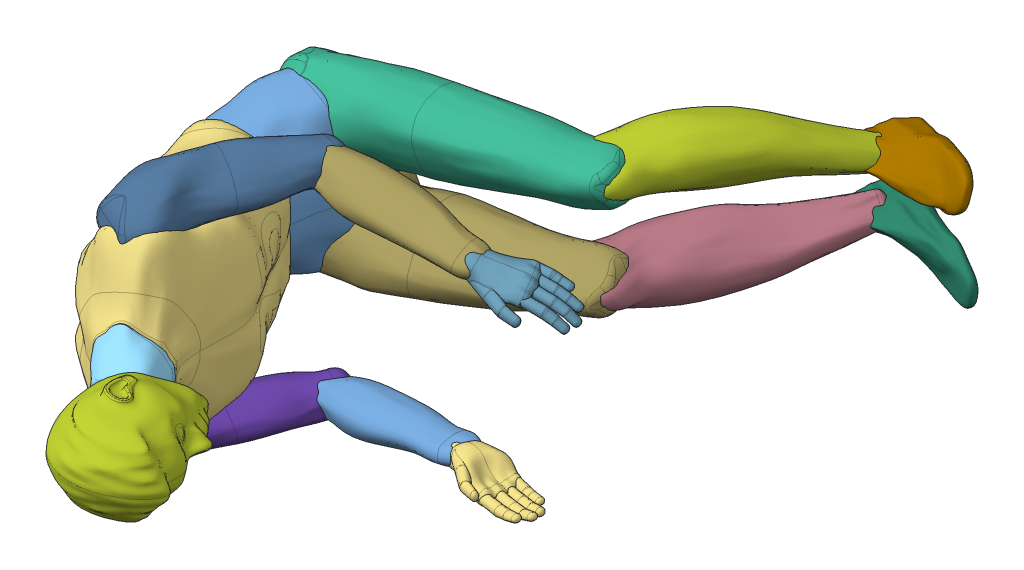
SolidWorks assembly Driving 95m, configuration Default. Lengths in mm.
Overall size (1011.36 605.8 1535.32).
33 component instances, 33 part files, 77 mates.
Components (placement in the parent):
- pelvis 95m-1: pelvis 95m [Default] at (-70.6587 0 44.4118) x (0.923258 0 0.384182) z (-0.384182 0 0.923258) size (268.99 352.68 356.07)
- waist joint 1 95m-1: waist joint 1 95m [Default] at (-43.3635 0 17.8605) x (0.923258 0 0.384182) z (-0.384182 0 0.923258) size (10 10 10)
- torso 95m-1: torso 95m [Default] at (-30.2769 0 72.4746) x (0.834779 0.001745 -0.550582) z (0.550583 0 0.834781) size (279.99 458.72 521.07)
- neck joint 1 95m-1: neck joint 1 95m [Default] at (163.4619 -5.0384 411.6074) x (-0.550071 0.045846 -0.833859) z (0.023786 0.998947 0.039231) size (10 10 10)
- neck 95m-1: neck 95m [Default] at (29.3282 16.2923 77.2377) x (0.899914 -0.004304 -0.436046) z (0.435418 -0.045676 0.899069) size (135.33 188.15 170)
- head joint 1 95m-1: head joint 1 95m [Default] at (211.6225 -4.6196 499.5308) x (0.892667 -0.107261 -0.437767) z (0.435418 -0.045676 0.899069) size (10 10 10)
- head 95m-1: head 95m [Default] at (34.0584 13.6624 75.1025) x (0.11643 0.993181 -0.005929) z (0.897605 -0.107778 -0.427422) size (191.83 255.04 223.91)
- left shoulder joint 1 95m-1: left shoulder joint 1 95m [Default] at (78.556 182.8743 368.6321) x (-0.943403 -0.001056 -0.331648) z (0.331647 0.00139 -0.943403) size (10 10 40)
- left shoulder joint 2 95m-1: left shoulder joint 2 95m [Default] at (83.5208 183.6245 354.5069) x (-0.025644 0.997233 0.069771) z (-0.330657 -0.074327 0.94082) size (10 10 15)
- left upper arm 95m-1: left upper arm 95m [Default] at (184.1882 -51.6436 111.104) x (0.938303 -0.132854 0.319277) z (-0.293182 0.184008 0.938182) size (146.61 142.15 380)
- left elbow joint 1 95m-1: left elbow joint 1 95m [Default] at (179.943 200 49.763) x (0.938765 -0.130385 0.318937) z (-0.293182 0.184008 0.938182) size (10 10 15)
- left lower arm 95m-1: left lower arm 95m [Default] at (143.696 -38.811 148.4892) x (-0.217376 -0.093758 -0.971575) z (0.959157 -0.205107 -0.194805) size (115.31 91.18 340)
- left hand joint 1 95m-1: left hand joint 1 95m [Default] at (469.8302 152.4 38.6111) x (-0.883779 0.213368 0.416424) z (0.188488 0.976917 -0.100524) size (10 10 10)
- left hand open 95m-1: left hand open 95m [Default] at (475.3213 155.0436 35.9783) x (0.358519 -0.148378 0.921655) z (0.827032 -0.407445 -0.387306) size (118.42 68.45 203.94)
- right shoulder joint 1 95m-1: right shoulder joint 1 95m [Default] at (77.0712 -173.1274 367.5038) x (-0.917198 -0.000953 -0.39843) z (0.398429 0.001462 -0.917198) size (10 10 40)
- right shoulder joint 2 95m-1: right shoulder joint 2 95m [Default] at (83.0509 -183.8955 353.7642) x (0.030025 0.996988 -0.071505) z (-0.397298 0.077547 0.914407) size (10 10 15)
- right upper arm 95m-1: right upper arm 95m [Default] at (232.823 46.2062 131.6122) x (0.91706 -0.003348 0.398735) z (-0.392556 -0.183133 0.901311) size (146.61 142.15 380)
- right elbow joint 1 95m-1: right elbow joint 1 95m [Default] at (202.1523 -200 57.1335) x (-0.89446 -0.152114 -0.420479) z (-0.392556 -0.183133 0.901311) size (10 10 15)
- right lower arm 95m-1: right lower arm 95m [Default] at (149.3924 38.5009 148.9771) x (-0.091707 0.086106 -0.992056) z (0.972496 0.221951 -0.070635) size (115.31 91.18 340)
- right hand joint 1 95m-1: right hand joint 1 95m [Default] at (491.0644 -152.4 87.8968) x (-0.9737 -0.211069 -0.085781) z (0.068872 0.086211 -0.993894) size (10 10 10)
- right hand open 95m-1: right hand open 95m [Default] at (496.8933 -151.8422 83.3184) x (-0.072866 0.088054 0.993447) z (0.997203 0.023041 0.0711) size (118.42 68.45 203.94)
- left leg joint 1 95m-1: left leg joint 1 95m [Default] at (-31.7988 60 -163.7871) x (0 1 0) z (0.977598 0 -0.210479) size (10 10 15)
- left leg joint 2 95m-1: left leg joint 2 95m [Default] at (-17.1638 60.7694 -166.9381) x (0.075215 -0.997036 -0.016194) z (-0.974701 -0.076939 0.209855) size (10 10 15)
- left upper leg 95m-1: left upper leg 95m [Default] at (-187.3688 -1.2482 -74.8289) x (0.183693 0.259165 0.948204) z (-0.974701 -0.076939 0.209855) size (222.04 178.33 598.24)
- left lower leg 95m-1: left lower leg 95m [Default] at (230.5191 137.9232 263.8845) x (0.896003 0.214779 0.38865) z (-0.425398 0.164184 0.889989) size (165.78 133.13 520)
- left foot joint 1 95m-1: left foot joint 1 95m [Default] at (556.1865 20 -704.7799) x (0.90494 0.065231 0.42051) z (-0.425398 0.164184 0.889989) size (10 10 10)
- left foot 95m-1: left foot 95m [Default] at (694.2276 -60.369 -713.7873) x (0.885142 0.072462 0.459644) z (-0.465191 0.161123 0.870423) size (271.62 105.92 120)
- right leg joint 1 95m-1: right leg joint 1 95m [Default] at (-31.816 -60 -163.8703) x (0 -1 0) z (0.981032 0 -0.193847) size (10 10 15)
- right leg joint 2 95m-1: right leg joint 2 95m [Default] at (-17.105 -59.6978 -166.7771) x (-0.029647 0.999543 0.005858) z (-0.980584 -0.03022 0.193759) size (10 10 15)
- right upper leg 95m-1: right upper leg 95m [Default] at (-198.0823 -3.5622 -93.3197) x (0.192143 0.049458 0.98012) z (-0.980584 -0.03022 0.193759) size (222.04 178.33 598.24)
- right lower leg 95m-1: right lower leg 95m [Default] at (225.4458 28.3839 264.8073) x (0.90568 0.05355 0.420566) z (-0.422145 0.022178 0.906257) size (165.78 133.13 520)
- right foot joint 1 95m-1: right foot joint 1 95m [Default] at (559.3881 -76 -702.5926) x (0.906093 -0.020673 0.422574) z (-0.422145 0.022178 0.906257) size (10 10 10)
- right foot 95m-1: right foot 95m [Default] at (697.0655 -4.2605 -739.8778) x (0.925475 -0.021722 0.378186) z (-0.377766 0.02115 0.92566) size (271.62 105.92 120)
Mates (geometry in assembly coordinates):
- Concentric1: concentric aligned: cylinder of torso 95m-1; cylinder of waist joint 1 95m-1
- Distance1: distance = 0 mm anti-aligned: plane of torso 95m-1 through (-45.2844 5 22.4768) normal (0 -1 0); plane of waist joint 1 95m-1 through (-51.8216 5 25.1722) normal (0 1 0)
- Concentric2: concentric aligned: cylinder of waist joint 1 95m-1; cylinder of pelvis 95m-1
- Distance2: distance = 0 mm anti-aligned: plane of waist joint 1 95m-1 through (-51.8216 -5 25.1722) normal (-0.384182 0 0.923258); plane of pelvis 95m-1 through (-47.2053 0 27.0931) normal (0.384182 0 -0.923258)
- Concentric3: concentric anti-aligned: cylinder of neck 95m-1; cylinder of neck joint 1 95m-1
- Distance3: distance = 0 mm anti-aligned: plane of neck 95m-1 through (163.6998 4.9511 411.9997) normal (-0.023786 -0.998947 -0.039231); plane of neck joint 1 95m-1 through (170.624 4.7306 413.4161) normal (0.023786 0.998947 0.039231)
- Concentric4: concentric anti-aligned: cylinder of neck joint 1 95m-1; cylinder of torso 95m-1
- Distance4: distance = 0 mm anti-aligned: plane of neck joint 1 95m-1 through (162.2762 4.7131 418.922) normal (-0.834779 -0.001745 0.550582); plane of torso 95m-1 through (159.4069 -0.0524 414.5565) normal (0.834779 0.001745 -0.550582)
- Concentric5: concentric aligned: cylinder of head 95m-1; cylinder of head joint 1 95m-1
- Distance5: distance = 0 mm anti-aligned: plane of head 95m-1 through (214.3818 0.1179 503.9965) normal (-0.11643 -0.993181 0.005929); plane of head joint 1 95m-1 through (212.0955 0.4259 510.6806) normal (0.11643 0.993181 -0.005929)
- Concentric6: concentric aligned: cylinder of head joint 1 95m-1; cylinder of neck 95m-1
- Distance6: distance = 0 mm anti-aligned: plane of head joint 1 95m-1 through (210.9312 -9.506 510.7399) normal (0.435418 -0.045676 0.899069); plane of neck 95m-1 through (215.9767 -5.0764 508.5215) normal (-0.435418 0.045676 -0.899069)
- Concentric7: concentric aligned: cylinder of left shoulder joint 1 95m-1; cylinder of torso 95m-1
- Distance7: distance = 0.0305 mm aligned: plane of left shoulder joint 1 95m-1 through (96.5462 177.9351 332.5494) normal (0.001457 -0.999998 -0.000961); plane of torso 95m-1 through (88.5127 177.916 340.3252) normal (0.001457 -0.999998 -0.000961)
- Concentric8: concentric anti-aligned: cylinder of left upper arm 95m-1; cylinder of left shoulder joint 2 95m-1
- Distance8: distance = 0 mm anti-aligned: plane of left upper arm 95m-1 through (83.5208 183.6245 354.5069) normal (-0.330657 -0.074327 0.94082); plane of left shoulder joint 2 95m-1 through (88.3661 178.6436 355.8162) normal (0.330657 0.074327 -0.94082)
- Concentric9: concentric aligned: cylinder of left shoulder joint 2 95m-1; cylinder of left shoulder joint 1 95m-1
- Distance9: distance = 0 mm aligned: plane of left shoulder joint 2 95m-1 through (83.4062 177.5287 369.9285) normal (0.943403 0.001056 0.331648); plane of left shoulder joint 1 95m-1 through (96.5462 177.9351 332.5494) normal (0.943403 0.001056 0.331648)
- Concentric10: concentric anti-aligned: cylinder of left lower arm 95m-1; cylinder of left elbow joint 1 95m-1
- Distance10: distance = 0 mm aligned: plane of left lower arm 95m-1 through (176.1061 196.9689 59.8173) normal (-0.181012 -0.974239 0.134514); plane of left elbow joint 1 95m-1 through (169.9464 198.5409 62.9136) normal (-0.181012 -0.974239 0.134514)
- Concentric11: concentric aligned: cylinder of left elbow joint 1 95m-1; cylinder of left upper arm 95m-1
- Distance11: distance = 0 mm anti-aligned: plane of left elbow joint 1 95m-1 through (174.3441 195.7807 48.8408) normal (0.293182 -0.184008 -0.938182); plane of left upper arm 95m-1 through (179.943 200 49.763) normal (-0.293182 0.184008 0.938182)
- Concentric12: concentric aligned: cylinder of left hand joint 1 95m-1; cylinder of left lower arm 95m-1
- Distance12: distance = 0 mm anti-aligned: plane of left hand joint 1 95m-1 through (473.9927 161.0506 31.0058) normal (0.188488 0.976917 -0.100524); plane of left lower arm 95m-1 through (471.7151 162.1692 37.6059) normal (-0.188488 -0.976917 0.100524)
- Concentric13: concentric aligned: cylinder of left hand open 95m-1; cylinder of left hand joint 1 95m-1
- Distance13: distance = 0 mm anti-aligned: plane of left hand open 95m-1 through (472.9139 157.3363 42.6265) normal (-0.428261 -0.01035 -0.903596); plane of left hand joint 1 95m-1 through (478.2753 161.1541 40.0418) normal (0.428261 0.01035 0.903596)
- Concentric14: concentric anti-aligned: cylinder of right shoulder joint 1 95m-1; cylinder of torso 95m-1
- Distance14: distance = 0 mm aligned: plane of right shoulder joint 1 95m-1 through (97.6017 -178.0641 332.8033) normal (-0.001457 0.999998 0.000961); plane of torso 95m-1 through (89.0314 -178.0835 339.9831) normal (-0.001457 0.999998 0.000961)
- Concentric15: concentric anti-aligned: cylinder of right upper arm 95m-1; cylinder of right shoulder joint 2 95m-1
- Distance15: distance = 0 mm anti-aligned: plane of right upper arm 95m-1 through (83.0509 -183.8955 353.7642) normal (-0.397298 0.077547 0.914407); plane of right shoulder joint 2 95m-1 through (87.4868 -188.8757 356.1138) normal (0.397298 -0.077547 -0.914407)
- Concentric16: concentric aligned: cylinder of right shoulder joint 2 95m-1; cylinder of right shoulder joint 1 95m-1
- Distance16: distance = 0 mm aligned: plane of right shoulder joint 2 95m-1 through (81.5273 -187.7125 369.8299) normal (0.917198 0.000953 0.39843); plane of right shoulder joint 1 95m-1 through (97.6017 -178.0641 332.8033) normal (0.917198 0.000953 0.39843)
- Concentric17: concentric anti-aligned: cylinder of right lower arm 95m-1; cylinder of right elbow joint 1 95m-1
- Distance17: distance = 0 mm aligned: plane of right lower arm 95m-1 through (197.1562 -196.9751 66.6671) normal (-0.214105 0.971248 0.104092); plane of right elbow joint 1 95m-1 through (199.6657 -197.1302 73.276) normal (-0.214105 0.971248 0.104092)
- Concentric18: concentric aligned: cylinder of right elbow joint 1 95m-1; cylinder of right upper arm 95m-1
- Distance18: distance = 0 mm anti-aligned: plane of right elbow joint 1 95m-1 through (205.5541 -194.3832 59.7564) normal (0.392556 0.183133 -0.901311); plane of right upper arm 95m-1 through (202.1523 -200 57.1335) normal (-0.392556 -0.183133 0.901311)
- Concentric19: concentric aligned: cylinder of right hand joint 1 95m-1; cylinder of right lower arm 95m-1
- Distance19: distance = 0 mm anti-aligned: plane of right hand joint 1 95m-1 through (497.7075 -155.3509 78.0398) normal (0.217176 -0.973662 -0.069407); plane of right lower arm 95m-1 through (492.4946 -156.8373 82.5803) normal (-0.217176 0.973662 0.069407)
- Concentric20: concentric aligned: cylinder of right hand open 95m-1; cylinder of right hand joint 1 95m-1
- Distance20: distance = 0 mm anti-aligned: plane of right hand open 95m-1 through (491.0644 -152.4 87.8968) normal (0.068872 0.086211 -0.993894); plane of right hand joint 1 95m-1 through (497.0187 -156.213 87.9787) normal (-0.068872 -0.086211 0.993894)
- Concentric21: concentric aligned: cylinder of left leg joint 1 95m-1; cylinder of pelvis 95m-1
- Distance21: distance = 0 mm anti-aligned: plane of left leg joint 1 95m-1 through (-18.1873 65 -171.8323) normal (0 1 0); plane of pelvis 95m-1 through (-26.9108 65 -164.8395) normal (0 -1 0)
- Concentric22: concentric anti-aligned: cylinder of left upper leg 95m-1; cylinder of left leg joint 2 95m-1
- Distance22: distance = 0 mm anti-aligned: plane of left upper leg 95m-1 through (-17.1638 60.7694 -166.9381) normal (-0.974701 -0.076939 0.209855); plane of left leg joint 2 95m-1 through (-18.5923 65.7546 -171.7451) normal (0.974701 0.076939 -0.209855)
- Concentric23: concentric aligned: cylinder of left leg joint 2 95m-1; cylinder of left leg joint 1 95m-1
- Distance23: distance = 0 mm aligned: plane of left leg joint 2 95m-1 through (-33.2128 64.6005 -168.5973) normal (-0.210479 0 -0.977598); plane of left leg joint 1 95m-1 through (-18.1873 55 -171.8323) normal (-0.210479 0 -0.977598)
- Concentric24: concentric aligned: cylinder of left lower leg 95m-1; cylinder of left upper leg 95m-1
- Distance24: distance = 0 mm aligned: plane of left lower leg 95m-1 through (404.5683 107.3988 -287.7495) normal (0.127341 -0.962764 0.238476); plane of left upper leg 95m-1 through (404.5683 107.3988 -287.7495) normal (0.127341 -0.962764 0.238476)
- Concentric25: concentric aligned: cylinder of left foot 95m-1; cylinder of left foot joint 1 95m-1
- Distance25: distance = 0 mm anti-aligned: plane of left foot 95m-1 through (554.1144 25.7423 -701.2116) normal (-0.010986 -0.984271 0.176325); plane of left foot joint 1 95m-1 through (547.4628 26.237 -698.8642) normal (0.010986 0.984271 -0.176325)
- Concentric26: concentric aligned: cylinder of left foot joint 1 95m-1; cylinder of left lower leg 95m-1
- Distance26: distance = 0 mm anti-aligned: plane of left foot joint 1 95m-1 through (547.3529 16.3943 -697.101) normal (-0.425398 0.164184 0.889989); plane of left lower leg 95m-1 through (551.9325 21.6418 -695.8801) normal (0.425398 -0.164184 -0.889989)
- Concentric27: concentric anti-aligned: cylinder of right leg joint 1 95m-1; cylinder of pelvis 95m-1
- Distance27: distance = 0 mm anti-aligned: plane of right leg joint 1 95m-1 through (-16.1313 -65 -161.8728) normal (0 -1 0); plane of pelvis 95m-1 through (-26.9108 -65 -164.8395) normal (0 1 0)
- Concentric28: concentric anti-aligned: cylinder of right upper leg 95m-1; cylinder of right leg joint 2 95m-1
- Distance28: distance = 0 mm anti-aligned: plane of right upper leg 95m-1 through (-17.105 -59.6978 -166.7771) normal (-0.980584 -0.03022 0.193759); plane of right leg joint 2 95m-1 through (-15.9875 -64.6955 -161.9012) normal (0.980584 0.03022 -0.193759)
- Concentric29: concentric aligned: cylinder of right leg joint 2 95m-1; cylinder of right leg joint 1 95m-1
- Distance29: distance = 0 mm aligned: plane of right leg joint 2 95m-1 through (-30.6963 -65.1488 -158.9949) normal (0.193847 0 0.981032); plane of right leg joint 1 95m-1 through (-16.1313 -55 -161.8728) normal (0.193847 0 0.981032)
- Concentric30: concentric aligned: cylinder of right lower leg 95m-1; cylinder of right upper leg 95m-1
- Distance30: distance = 0 mm aligned: plane of right lower leg 95m-1 through (410.3353 -67.6036 -275.6807) normal (-0.039203 0.998319 -0.042692); plane of right upper leg 95m-1 through (410.3353 -67.6036 -275.6807) normal (-0.039203 0.998319 -0.042692)
- Concentric31: concentric anti-aligned: cylinder of right foot 95m-1; cylinder of right foot joint 1 95m-1
- Distance31: distance = 0 mm anti-aligned: plane of right foot 95m-1 through (557.1368 -80.8868 -698.0045) normal (0.028106 0.99954 -0.011368); plane of right foot joint 1 95m-1 through (550.4956 -80.6726 -695.586) normal (-0.028106 -0.99954 0.011368)
- Concentric32: concentric aligned: cylinder of right foot joint 1 95m-1; cylinder of right lower leg 95m-1
- Distance32: distance = 0 mm anti-aligned: plane of right foot joint 1 95m-1 through (550.4956 -80.6726 -695.586) normal (-0.422145 0.022178 0.906257); plane of right lower leg 95m-1 through (555.1666 -75.7782 -693.53) normal (0.422145 -0.022178 -0.906257)
- Coincident6: coincident: unknown of pelvis 95m-1
- Distance33: distance = 76 mm: point of right foot joint 1 95m-1
- Distance34: distance = 20 mm: unknown of left foot joint 1 95m-1
- Coincident11: coincident aligned: unknown of waist joint 1 95m-1
- Distance35: distance = 152.4 mm: unknown of right hand joint 1 95m-1
- Distance36: distance = 152.4 mm: unknown of left hand joint 1 95m-1
- Distance38: distance = 800 mm: point of right leg joint 1 95m-1; point of right foot joint 1 95m-1
- Distance39: distance = 800 mm: point of left foot joint 1 95m-1; point of left leg joint 1 95m-1
- Distance40: distance = 200 mm: unknown of right elbow joint 1 95m-1
- Distance41: distance = 200 mm: unknown of left elbow joint 1 95m-1
- Distance43: distance = 500 mm: point of left shoulder joint 2 95m-1; point of left hand joint 1 95m-1
- Distance44: distance = 500 mm: point of right hand joint 1 95m-1; point of right shoulder joint 1 95m-1
- Angle2: planar angle = 0.977384 rad aligned: plane of torso 95m-1 through (-30.2769 0 72.4746) normal (0.834779 0.001745 -0.550582); plane of pelvis 95m-1 through (-70.6587 0 44.4118) normal (0.923258 0 0.384182)
